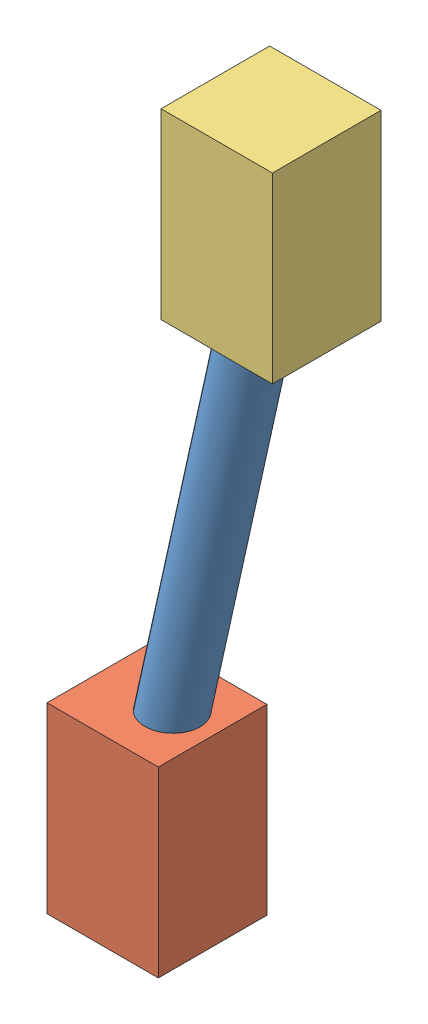
SolidWorks assembly Arm Assembly, configuration Default. Lengths in mm.
Overall size (52.71 176.36 25.4).
3 component instances, 3 part files, 3 mates.
Components (placement in the parent):
- Arm-1: Arm [Default] at (41.2966 99.4107 38.9811) x (0.953154 -0.211309 0.21644) z (-0.21644 -0.976296 0) size (12.7 12.7 152.4)
- Arm To Base Mount-3: Arm To Base Mount [Default] at (27.9576 32.5914 26.5839) size (26.04 48.12 25.4)
- MotorMount-2: MotorMount [Default] at (54.6356 166.2301 26.5839) x (-1 0 0) z (0 0 1) size (26.04 48.12 25.4)
Mates (geometry in assembly coordinates):
- Coincident5: coincident aligned: circle of Arm-1; circle of Arm To Base Mount-3
- Coincident6: coincident anti-aligned: circle of Arm-1; circle of MotorMount-2
- Parallel2: parallel aligned: plane of Arm To Base Mount-3 through (40.9751 11.23 51.9839) normal (1 0 0); plane of MotorMount-2 through (67.6531 187.5915 51.9839) normal (1 0 0)
